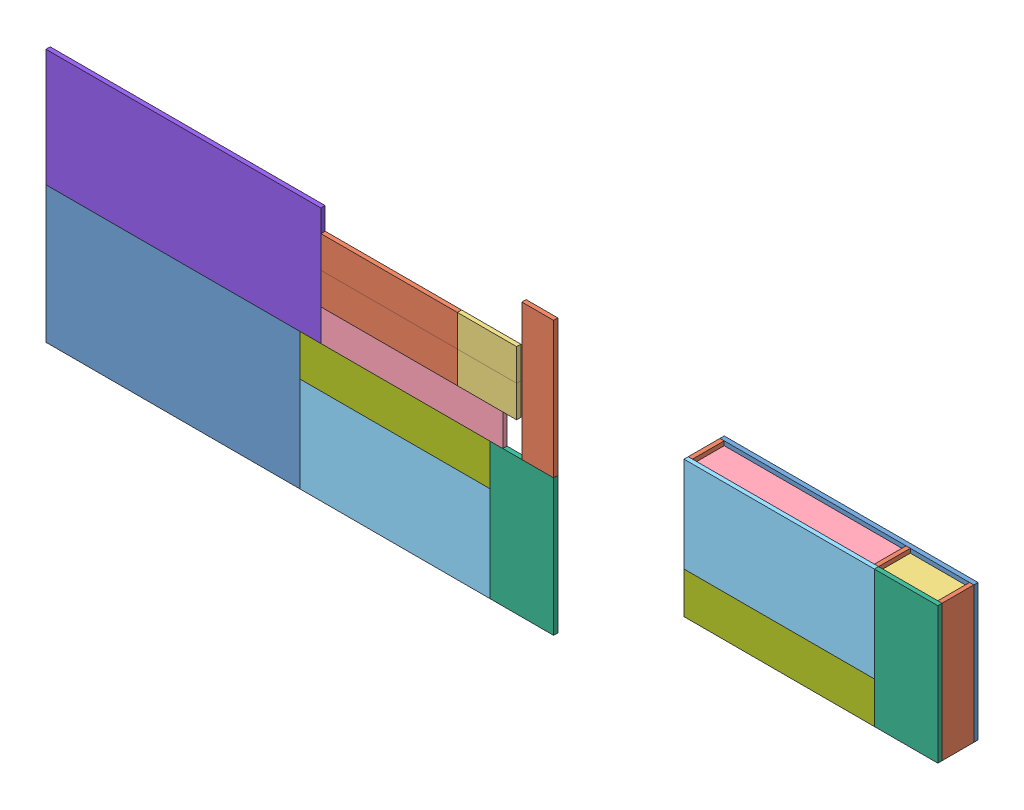
SolidWorks assembly Mesa, configuration Predeterminado. Lengths in mm.
Overall size (4386.65 1290 190).
21 component instances, 8 part files, 61 mates.
Components (placement in the parent):
- Base-1: Base [Predeterminado] at (-601.9839 341.5591 1200) size (1200 645 20)
- Lateral-1: Lateral [Predeterminado] at (-653.2525 -53.4435 1230.5206) x (0 -1 0) z (-1 0 0) size (645 150 20)
- Lateral-2: Lateral [Predeterminado] at (506.7475 136.3495 1230.5206) x (0 1 0) z (1 0 0) size (645 150 20)
- Lateral-3: Lateral [Predeterminado] at (206.7475 136.3495 1230.5206) x (0 1 0) z (1 0 0) size (645 150 20)
- Short-1: Short [Predeterminado] at (393.3318 -241.047 1280.2521) x (1 0 0) z (0 -1 0) size (280 150 20)
- Short-2: Short [Predeterminado] at (393.3318 343.953 1280.2521) x (1 0 0) z (0 -1 0) size (280 150 20)
- Long-1: Long [Predeterminado] at (-39.2994 343.953 1133.1767) x (1 0 0) z (0 -1 0) size (860 150 20)
- Top_Principal-1: Top_Principal [Predeterminado] at (-112.993 71.9845 1370) size (900 450 20)
- Top_Lateral-1: Top_Lateral [Predeterminado] at (287.0409 7.0831 1370) x (0 -1 0) z (0 0 1) size (645 300 20)
- Top_Fijo-1: Top_Fijo [Predeterminado] at (-156.8117 -416.3131 1370) size (900 195 20)
- Mesa_Papa-1: Mesa_Papa [Predeterminado] at (-3254.9464 153.6589 1200) size (1300 555 20)
- Base-2: Base [Predeterminado] at (-3788.6329 -213.4409 1200) size (1200 645 20)
- Lateral-4: Lateral [Predeterminado] at (-2332.2981 248.4324 1200) x (-1 0 0) z (0 0 1) size (645 150 20)
- Lateral-5: Lateral [Predeterminado] at (-2142.505 -30.5264 1200) size (645 150 20)
- Lateral-6: Lateral [Predeterminado] at (-1470.4221 226.3495 1200) x (0 1 0) z (0 0 1) size (645 150 20)
- Short-3: Short [Predeterminado] at (-1748.3172 48.7009 1220) x (1 0 0) z (0 0 -1) size (280 150 20)
- Short-4: Short [Predeterminado] at (-1748.3172 169.2051 1200) size (280 150 20)
- Long-2: Long [Predeterminado] at (-1945.9484 -277.8703 1200) size (860 150 20)
- Top_Principal-2: Top_Principal [Predeterminado] at (-2099.642 -678.0155 1200) size (900 450 20)
- Top_Lateral-3: Top_Lateral [Predeterminado] at (-1699.6081 -547.9169 1200) x (0 -1 0) z (0 0 1) size (645 300 20)
- Top_Fijo-3: Top_Fijo [Predeterminado] at (-2276.3424 -55.7809 1200) x (-1 0 0) z (0 0 1) size (900 195 20)
Mates (geometry in assembly coordinates):
- Coincidente1: coincident anti-aligned: plane of Base-1 through (-601.9839 341.5591 1220) normal (0 0 1); plane of Lateral-1 through (-673.2525 363.953 1220) normal (0 0 -1)
- Coincidente2: coincident aligned: plane of Base-1 through (-673.2525 363.953 1220) normal (-1 0 0); plane of Lateral-1 through (-673.2525 -53.4435 1230.5206) normal (-1 0 0)
- Coincidente3: coincident aligned: plane of Base-1 through (-673.2525 -281.047 1220) normal (0 -1 0); plane of Lateral-1 through (-673.2525 -281.047 1370) normal (0 -1 0)
- Coincidente4: coincident anti-aligned: plane of Base-1 through (-601.9839 341.5591 1220) normal (0 0 1); plane of Lateral-2 through (526.7475 -281.047 1220) normal (0 0 -1)
- Coincidente5: coincident aligned: plane of Base-1 through (526.7475 363.953 1220) normal (1 0 0); plane of Lateral-2 through (526.7475 136.3495 1230.5206) normal (1 0 0)
- Coincidente6: coincident aligned: plane of Base-1 through (-673.2525 -281.047 1220) normal (0 -1 0); plane of Lateral-2 through (526.7475 -281.047 1370) normal (0 -1 0)
- Coincidente7: coincident anti-aligned: plane of Base-1 through (-601.9839 341.5591 1220) normal (0 0 1); plane of Lateral-3 through (226.7475 -281.047 1220) normal (0 0 -1)
- Coincidente8: coincident aligned: plane of Base-1 through (-673.2525 -281.047 1220) normal (0 -1 0); plane of Lateral-3 through (226.7475 -281.047 1370) normal (0 -1 0)
- Distancia1: distance = 900 mm anti-aligned: plane of Lateral-1 through (-673.2525 -53.4435 1230.5206) normal (-1 0 0); plane of Lateral-3 through (226.7475 136.3495 1230.5206) normal (1 0 0)
- Coincidente10: coincident anti-aligned: plane of Base-1 through (-601.9839 341.5591 1220) normal (0 0 1); plane of Short-1 through (226.7475 -261.047 1220) normal (0 0 -1)
- Coincidente11: coincident anti-aligned: plane of Lateral-2 through (506.7475 136.3495 1230.5206) normal (-1 0 0); plane of Short-1 through (506.7475 -261.047 1370) normal (1 0 0)
- Distancia2: distance = 20 mm aligned: plane of Short-1 through (393.3318 -261.047 1280.2521) normal (0 -1 0); plane of Lateral-3 through (226.7475 -281.047 1370) normal (0 -1 0)
- Coincidente13: coincident anti-aligned: plane of Base-1 through (-601.9839 341.5591 1220) normal (0 0 1); plane of Short-2 through (226.7475 323.953 1220) normal (0 0 -1)
- Coincidente14: coincident anti-aligned: plane of Lateral-3 through (226.7475 136.3495 1230.5206) normal (1 0 0); plane of Short-2 through (226.7475 323.953 1370) normal (-1 0 0)
- Distancia3: distance = 20 mm aligned: plane of Short-2 through (393.3318 343.953 1280.2521) normal (0 1 0); plane of Lateral-2 through (526.7475 363.953 1370) normal (0 1 0)
- Coincidente16: coincident anti-aligned: plane of Base-1 through (-601.9839 341.5591 1220) normal (0 0 1); plane of Long-1 through (-653.2525 323.953 1220) normal (0 0 -1)
- Coincidente17: coincident anti-aligned: plane of Lateral-1 through (-653.2525 -53.4435 1230.5206) normal (1 0 0); plane of Long-1 through (-653.2525 323.953 1370) normal (-1 0 0)
- Distancia4: distance = 20 mm aligned: plane of Long-1 through (-39.2994 343.953 1133.1767) normal (0 1 0); plane of Lateral-1 through (-673.2525 363.953 1370) normal (0 1 0)
- Coincidente19: coincident anti-aligned: plane of Lateral-1 through (-673.2525 363.953 1370) normal (0 0 1); plane of Top_Principal-1 through (-112.993 71.9845 1370) normal (0 0 -1)
- Coincidente20: coincident aligned: plane of Lateral-1 through (-673.2525 -53.4435 1230.5206) normal (-1 0 0); plane of Top_Principal-1 through (-673.2525 363.953 1390) normal (-1 0 0)
- Coincidente21: coincident aligned: plane of Lateral-1 through (-673.2525 363.953 1370) normal (0 1 0); plane of Top_Principal-1 through (-673.2525 363.953 1390) normal (0 1 0)
- Coincidente22: coincident anti-aligned: plane of Lateral-2 through (526.7475 -281.047 1370) normal (0 0 1); plane of Top_Lateral-1 through (287.0409 7.0831 1370) normal (0 0 -1)
- Coincidente23: coincident aligned: plane of Lateral-3 through (226.7475 -281.047 1370) normal (0 -1 0); plane of Top_Lateral-1 through (526.7475 -281.047 1390) normal (0 -1 0)
- Coincidente24: coincident aligned: plane of Lateral-2 through (526.7475 136.3495 1230.5206) normal (1 0 0); plane of Top_Lateral-1 through (526.7475 363.953 1390) normal (1 0 0)
- Coincidente25: coincident anti-aligned: plane of Lateral-1 through (-673.2525 363.953 1370) normal (0 0 1); plane of Top_Fijo-1 through (-156.8117 -416.3131 1370) normal (0 0 -1)
- Coincidente26: coincident aligned: plane of Lateral-1 through (-673.2525 -281.047 1370) normal (0 -1 0); plane of Top_Fijo-1 through (-673.2525 -281.047 1390) normal (0 -1 0)
- Coincidente27: coincident aligned: plane of Lateral-1 through (-673.2525 -53.4435 1230.5206) normal (-1 0 0); plane of Top_Fijo-1 through (-673.2525 -86.047 1390) normal (-1 0 0)
- Coincidente28: coincident aligned: plane of Base-1 through (-601.9839 341.5591 1200) normal (0 0 -1); plane of Mesa_Papa-1 through (-3254.9464 153.6589 1200) normal (0 0 -1)
- Coincidente29: coincident aligned: plane of Base-1 through (-673.2525 363.953 1220) normal (0 1 0); plane of Mesa_Papa-1 through (-3859.9015 363.953 1220) normal (0 1 0)
- Coincidente30: coincident aligned: plane of Mesa_Papa-1 through (-3254.9464 153.6589 1200) normal (0 0 -1); plane of Base-2 through (-3788.6329 -213.4409 1200) normal (0 0 -1)
- Coincidente31: coincident anti-aligned: plane of Mesa_Papa-1 through (-3859.9015 -191.047 1220) normal (0 -1 0); plane of Base-2 through (-3859.9015 -191.047 1220) normal (0 1 0)
- Coincidente32: coincident aligned: plane of Mesa_Papa-1 through (-3859.9015 363.953 1220) normal (-1 0 0); plane of Base-2 through (-3859.9015 -191.047 1220) normal (-1 0 0)
- Coincidente33: coincident aligned: plane of Base-2 through (-3788.6329 -213.4409 1220) normal (0 0 1); plane of Top_Principal-2 through (-2099.642 -678.0155 1220) normal (0 0 1)
- Coincidente34: coincident aligned: plane of Lateral-4 through (-2332.2981 248.4324 1220) normal (0 0 1); plane of Top_Principal-2 through (-2099.642 -678.0155 1220) normal (0 0 1)
- Coincidente35: coincident aligned: plane of Lateral-5 through (-2142.505 -30.5264 1220) normal (0 0 1); plane of Top_Principal-2 through (-2099.642 -678.0155 1220) normal (0 0 1)
- Coincidente36: coincident aligned: plane of Lateral-6 through (-1470.4221 427.3825 1220) normal (0 0 1); plane of Top_Principal-2 through (-2099.642 -678.0155 1220) normal (0 0 1)
- Coincidente37: coincident aligned: plane of Short-4 through (-1748.3172 169.2051 1220) normal (0 0 1); plane of Top_Principal-2 through (-2099.642 -678.0155 1220) normal (0 0 1)
- Coincidente40: coincident aligned: plane of Top_Principal-2 through (-2058.9656 -674.8444 1200) normal (0 0 -1); plane of Short-5 through (-2004.5243 -659.6316 1200) normal (0 0 -1)
- Coincidente41: coincident aligned: plane of Short-3 through (-1077.8403 276.2777 1200) normal (0 0 -1); plane of Short-5 through (-2004.5243 -659.6316 1200) normal (0 0 -1)
- Coincidente42: coincident aligned: plane of Long-2 through (-1945.9484 -277.8703 1220) normal (0 0 1); plane of Top_Principal-2 through (-2099.642 -678.0155 1220) normal (0 0 1)
- Coincidente43: coincident aligned: plane of Top_Principal-2 through (-2099.642 -678.0155 1220) normal (0 0 1); plane of Top_Fijo-3 through (-2276.3424 -55.7809 1220) normal (0 0 1)
- Coincidente44: coincident aligned: plane of Top_Principal-2 through (-2099.642 -678.0155 1220) normal (0 0 1); plane of Top_Lateral-3 through (-1699.6081 -547.9169 1220) normal (0 0 1)
- Coincidente46: coincident aligned: plane of Lateral-5 through (-2142.505 -30.5264 1200) normal (0 0 -1); plane of Short-3 through (-1748.3172 48.7009 1200) normal (0 0 -1)
- Coincidente47: coincident anti-aligned: plane of Base-2 through (-2659.9015 -191.047 1220) normal (1 0 0); plane of Top_Principal-2 through (-2659.9015 -386.047 1220) normal (-1 0 0)
- Coincidente48: coincident aligned: plane of Base-2 through (-3859.9015 -836.047 1220) normal (0 -1 0); plane of Top_Principal-2 through (-2659.9015 -836.047 1220) normal (0 -1 0)
- Coincidente49: coincident anti-aligned: plane of Base-2 through (-2659.9015 -191.047 1220) normal (1 0 0); plane of Top_Fijo-3 through (-2659.9015 -386.047 1220) normal (-1 0 0)
- Coincidente50: coincident anti-aligned: plane of Top_Principal-2 through (-2659.9015 -386.047 1220) normal (0 1 0); plane of Top_Fijo-3 through (-1759.9015 -386.047 1220) normal (0 -1 0)
- Coincidente51: coincident anti-aligned: plane of Mesa_Papa-1 through (-2559.9015 363.953 1220) normal (1 0 0); plane of Long-2 through (-2559.9015 -41.047 1220) normal (-1 0 0)
- Coincidente52: coincident anti-aligned: plane of Long-2 through (-2559.9015 -191.047 1220) normal (0 -1 0); plane of Top_Fijo-3 through (-1759.9015 -191.047 1220) normal (0 1 0)
- Coincidente53: coincident anti-aligned: plane of Mesa_Papa-1 through (-2559.9015 363.953 1220) normal (1 0 0); plane of Lateral-5 through (-2559.9015 108.953 1220) normal (-1 0 0)
- Coincidente54: coincident anti-aligned: plane of Lateral-5 through (-2559.9015 -41.047 1220) normal (0 -1 0); plane of Long-2 through (-2559.9015 -41.047 1220) normal (0 1 0)
- Coincidente55: coincident anti-aligned: plane of Mesa_Papa-1 through (-2559.9015 363.953 1220) normal (1 0 0); plane of Lateral-4 through (-2559.9015 108.953 1220) normal (-1 0 0)
- Coincidente56: coincident anti-aligned: plane of Lateral-4 through (-1914.9015 108.953 1220) normal (0 -1 0); plane of Lateral-5 through (-2559.9015 108.953 1220) normal (0 1 0)
- Coincidente57: coincident aligned: plane of Top_Principal-2 through (-2659.9015 -836.047 1220) normal (0 -1 0); plane of Top_Lateral-3 through (-1459.9015 -836.047 1220) normal (0 -1 0)
- Coincidente58: coincident anti-aligned: plane of Top_Principal-2 through (-1759.9015 -386.047 1220) normal (1 0 0); plane of Top_Lateral-3 through (-1759.9015 -191.047 1220) normal (-1 0 0)
- Coincidente59: coincident anti-aligned: plane of Lateral-5 through (-1914.9015 108.953 1220) normal (1 0 0); plane of Short-3 through (-1914.9015 -41.047 1200) normal (-1 0 0)
- Coincidente60: coincident anti-aligned: plane of Short-3 through (-1914.9015 -41.047 1200) normal (0 -1 0); plane of Long-2 through (-2559.9015 -41.047 1220) normal (0 1 0)
- Coincidente61: coincident anti-aligned: plane of Lateral-4 through (-1914.9015 108.953 1220) normal (1 0 0); plane of Short-4 through (-1914.9015 258.953 1220) normal (-1 0 0)
- Coincidente62: coincident anti-aligned: plane of Short-3 through (-1914.9015 108.953 1200) normal (0 1 0); plane of Short-4 through (-1914.9015 108.953 1220) normal (0 -1 0)
- Coincidente63: coincident aligned: plane of Lateral-6 through (-1459.9015 -191.047 1220) normal (1 0 0); plane of Top_Lateral-3 through (-1459.9015 -191.047 1220) normal (1 0 0)
- Coincidente64: coincident anti-aligned: plane of Lateral-6 through (-1609.9015 -191.047 1220) normal (0 -1 0); plane of Top_Lateral-3 through (-1459.9015 -191.047 1220) normal (0 1 0)
